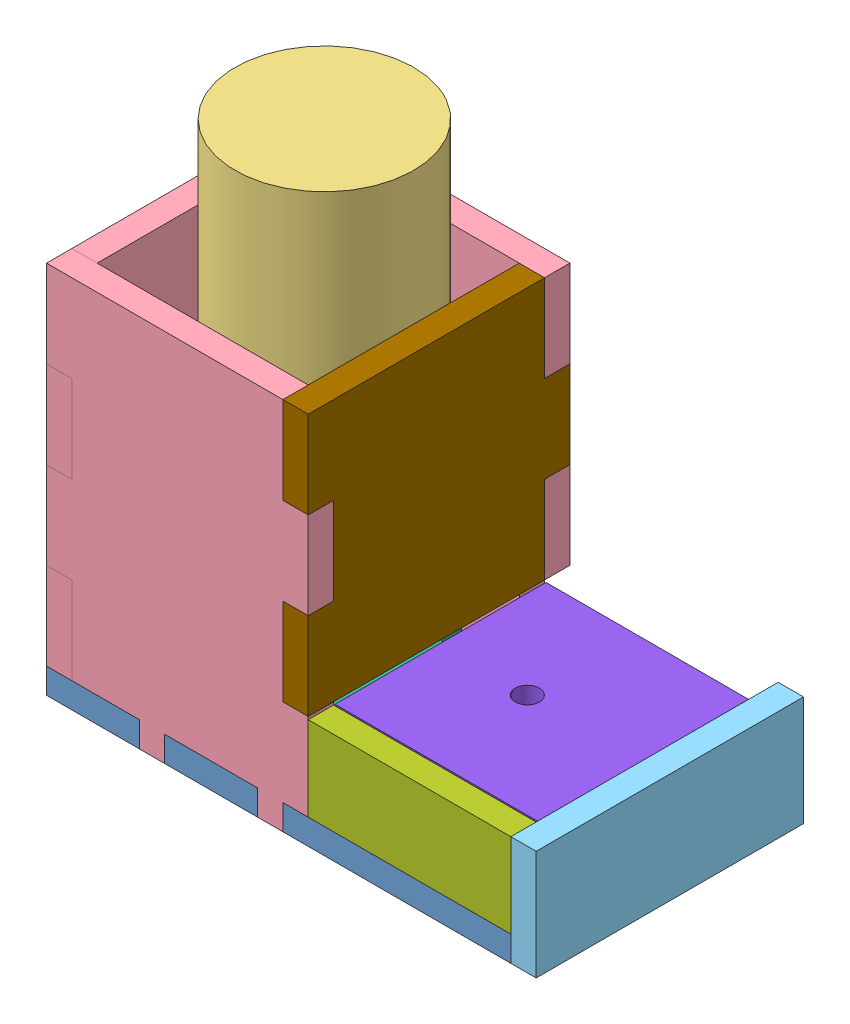
SolidWorks assembly gearbox, configuration Default. Lengths in mm.
Overall size (87.03 89.87 50.25).
12 component instances, 9 part files, 33 mates.
Components (placement in the parent):
- gearbox-box-1: gearbox-box [Default] at (5.1621 -9.0788 3.444) size (82.5 4.5 46.5)
- gearbox-motor front-1: gearbox-motor front [Default] at (-12.8379 10.9212 3.444) x (0 0 -1) z (0 -1 0) size (37.5 37.5 4.5)
- Motor Barber Coleman geared-1: Motor Barber Coleman geared [Default] at (-12.838 29.1584 0.569) x (0 1 0) z (-0.41578 0 0.909465) size (89.87 35.14 35.14)
- gearbox-motor sides-3: gearbox-motor sides [Default] at (-36.0879 26.4212 1.194) x (0 0 -1) z (0 -1 0) size (46.5 4.5 66.5)
- gearbox-motor sides-4: gearbox-motor sides [Default] at (-10.5879 26.4212 -19.806) x (1 0 0) z (0 -1 0) size (46.5 4.5 66.5)
- gearbox-leadscrew back-1: gearbox-leadscrew back [Default] at (50.9121 0.6712 2.944) x (0 0 1) z (0 -1 0) size (47.5 4.5 19.5)
- spur gear_am-1: spur gear_am [Metric - Spur gear 2.5M 12T 14.5PA 5FW ---S12N75H50L5N] at (26.0912 0.4212 3.444) x (0 -1 0) z (0.997105 0 -0.07604) size (5 34.15 34.15)
- spur gear_am-2: spur gear_am [Metric - Spur gear 2.5M 12T 14.5PA 5FW ---S12N75H50L5N] at (-4.9088 0.4212 3.444) x (0 -1 0) z (0.658618 0 0.752477) size (5 34.15 34.15)
- gearbox-motor sides-6: gearbox-motor sides [Default] at (-15.0879 26.4212 26.694) x (-1 0 0) z (0 -1 0) size (46.5 4.5 66.5)
- gearbox-box new sides-1: gearbox-box new sides [Default] at (46.3637 -3.7922 22.194) x (1 0 0) z (0 -1 0) size (36 4.5 15)
- gearbox-leadscrew new upper roof-1: gearbox-leadscrew new upper roof [Default] at (21.7467 5.9212 12.3291) x (-1 0 0) z (0 0 -1) size (36 4.5 37.5)
- gearbox-motor sides B-2: gearbox-motor sides B [Default] at (5.9121 41.9212 5.694) x (0 0 1) z (0 1 0) size (46.5 4.5 46.5)
Mates (geometry in assembly coordinates):
- Concentric7: concentric aligned: cylinder of gearbox-motor front-1 through (-4.9088 6.4212 4.194) axis (0 1 0) radius 2.75; cylinder of Motor Barber Coleman geared-1 through (-4.9088 -11.6848 4.194) axis (0 1 0) radius 2.3749
- Coincident27: coincident anti-aligned: plane of gearbox-motor front-1 through (-12.8379 10.9212 3.444) normal (0 1 0); plane of Motor Barber Coleman geared-1 through (-12.838 10.9212 0.569) normal (0 -1 0)
- Coincident28: coincident aligned: plane of gearbox-box-1 through (-36.0879 -4.5788 -19.806) normal (-1 0 0); plane of gearbox-motor sides-3 through (-36.0879 26.4212 1.194) normal (-1 0 0)
- Coincident60: coincident anti-aligned: plane of gearbox-box-1 through (46.4121 -4.5788 -19.806) normal (1 0 0); plane of gearbox-leadscrew back-1 through (46.4121 0.6712 2.944) normal (-1 0 0)
- Concentric8: concentric anti-aligned: cylinder of gearbox-box-1 through (26.0912 -4.5788 3.444) axis (0 -1 0) radius 2.05; cylinder of spur gear_am-1 through (26.0912 -49.5788 3.444) axis (0 1 0) radius 2.5
- Concentric9: concentric anti-aligned: cylinder of gearbox-box-1 through (-4.9088 -4.5788 3.444) axis (0 -1 0) radius 2.05; cylinder of spur gear_am-2 through (-4.9088 -49.5788 3.444) axis (0 1 0) radius 2.5
- Coincident71: coincident anti-aligned: plane of gearbox-box-1 through (5.1621 -4.5788 3.444) normal (0 1 0); plane of spur gear_am-1 through (26.0912 -4.5788 3.444) normal (0 -1 0)
- Coincident72: coincident anti-aligned: plane of gearbox-box-1 through (5.1621 -4.5788 3.444) normal (0 1 0); plane of spur gear_am-2 through (-4.9088 -4.5788 3.444) normal (0 -1 0)
- Coincident73: coincident aligned: plane of gearbox-motor sides-3 through (-31.5879 41.9212 -19.806) normal (0 0 -1); plane of gearbox-motor sides-4 through (-10.5879 26.4212 -19.806) normal (0 0 -1)
- Coincident74: coincident aligned: plane of gearbox-motor sides-3 through (-31.5879 57.4212 22.194) normal (0 1 0); plane of gearbox-motor sides-4 through (-31.5879 57.4212 -15.306) normal (0 1 0)
- Coincident75: coincident aligned: plane of gearbox-motor sides-3 through (-36.0879 26.4212 1.194) normal (-1 0 0); plane of gearbox-motor sides-4 through (-36.0879 41.9212 -15.306) normal (-1 0 0)
- Coincident82: coincident aligned: plane of gearbox-motor sides-3 through (-31.5879 41.9212 26.694) normal (0 0 1); plane of gearbox-motor sides-6 through (-15.0879 26.4212 26.694) normal (0 0 1)
- Coincident84: coincident aligned: plane of gearbox-motor sides-3 through (-36.0879 26.4212 1.194) normal (-1 0 0); plane of gearbox-motor sides-6 through (-36.0879 41.9212 22.194) normal (-1 0 0)
- Coincident85: coincident anti-aligned: plane of gearbox-motor front-1 through (5.9121 6.4212 22.194) normal (0 0 1); plane of gearbox-motor sides-6 through (-15.0879 26.4212 22.194) normal (0 0 -1)
- Parallel1: parallel aligned: plane of gearbox-motor front-1 through (-12.8379 6.4212 3.444) normal (0 -1 0); plane of gearbox-motor sides-4 through (-27.0879 -4.5788 -15.306) normal (0 -1 0)
- Coincident87: coincident anti-aligned: plane of gearbox-motor front-1 through (-31.5879 6.4212 22.194) normal (-1 0 0); plane of gearbox-motor sides-3 through (-31.5879 26.4212 1.194) normal (1 0 0)
- Coincident90: coincident aligned: plane of gearbox-box-1 through (-36.0879 -4.5788 -19.806) normal (0 0 -1); plane of gearbox-motor sides-4 through (-10.5879 26.4212 -19.806) normal (0 0 -1)
- Coincident91: coincident aligned: plane of gearbox-box-1 through (5.1621 -9.0788 3.444) normal (0 -1 0); plane of gearbox-leadscrew back-1 through (46.4121 -9.0788 -20.806) normal (0 -1 0)
- Coincident92: coincident aligned: plane of gearbox-box-1 through (-36.0879 -4.5788 26.694) normal (0 0 1); plane of gearbox-leadscrew back-1 through (46.4121 10.4212 26.694) normal (0 0 1)
- Coincident93: coincident anti-aligned: plane of gearbox-box-1 through (5.1621 -4.5788 3.444) normal (0 1 0); plane of gearbox-box new sides-1 through (10.4121 -4.5788 26.694) normal (0 -1 0)
- Coincident94: coincident anti-aligned: plane of gearbox-leadscrew back-1 through (46.4121 0.6712 2.944) normal (-1 0 0); plane of gearbox-box new sides-1 through (46.4121 10.4212 26.694) normal (1 0 0)
- Coincident95: coincident aligned: plane of gearbox-box-1 through (-36.0879 -4.5788 26.694) normal (0 0 1); plane of gearbox-box new sides-1 through (46.3637 -3.7922 26.694) normal (0 0 1)
- Concentric11: concentric aligned: cylinder of spur gear_am-1 through (26.0912 -49.5788 3.444) axis (0 1 0) radius 2.5; cylinder of gearbox-leadscrew new upper roof-1 through (26.0912 5.9212 3.444) axis (0 1 0) radius 2.15
- Coincident106: coincident anti-aligned: plane of gearbox-leadscrew back-1 through (46.4121 0.6712 2.944) normal (-1 0 0); plane of gearbox-leadscrew new upper roof-1 through (46.4112 10.4212 21.944) normal (1 0 0)
- Coincident107: coincident aligned: plane of gearbox-leadscrew back-1 through (46.4121 10.4212 -20.806) normal (0 1 0); plane of gearbox-leadscrew new upper roof-1 through (21.7467 10.4212 12.3291) normal (0 1 0)
- Coincident113: coincident anti-aligned: plane of gearbox-motor sides-6 through (10.4121 41.9212 22.194) normal (0 1 0); plane of gearbox-motor sides B-2 through (10.4121 41.9212 22.194) normal (0 -1 0)
- Coincident114: coincident aligned: plane of gearbox-motor sides-6 through (-15.0879 26.4212 26.694) normal (0 0 1); plane of gearbox-motor sides B-2 through (10.4121 57.4212 26.694) normal (0 0 1)
- Coincident115: coincident anti-aligned: plane of gearbox-motor sides-6 through (5.9121 57.4212 22.194) normal (1 0 0); plane of gearbox-motor sides B-2 through (5.9121 41.9212 5.694) normal (-1 0 0)
- Coincident116: coincident anti-aligned: plane of gearbox-motor front-1 through (5.9121 6.4212 -15.306) normal (1 0 0); plane of gearbox-motor sides B-2 through (5.9121 41.9212 5.694) normal (-1 0 0)
- Coincident117: coincident anti-aligned: plane of gearbox-motor front-1 through (-12.8379 10.9212 3.444) normal (0 1 0); plane of gearbox-motor sides B-2 through (10.4121 10.9212 -15.306) normal (0 -1 0)
- Tangent1: tangent anti-aligned: cylinder of Motor Barber Coleman geared-1 through (-12.838 78.1804 0.569) axis (0 -1 0) radius 15.875; plane of gearbox-motor sides-4 through (-10.5879 26.4212 -15.306) normal (0 0 1)
- Coincident118: coincident anti-aligned: plane of gearbox-box-1 through (5.1621 -4.5788 3.444) normal (0 1 0); plane of gearbox-motor sides-6 through (1.4121 -4.5788 22.194) normal (0 -1 0)
- Coincident119: coincident aligned: plane of gearbox-motor sides-4 through (-31.5879 57.4212 -15.306) normal (0 1 0); plane of gearbox-motor sides B-2 through (10.4121 57.4212 22.194) normal (0 1 0)
